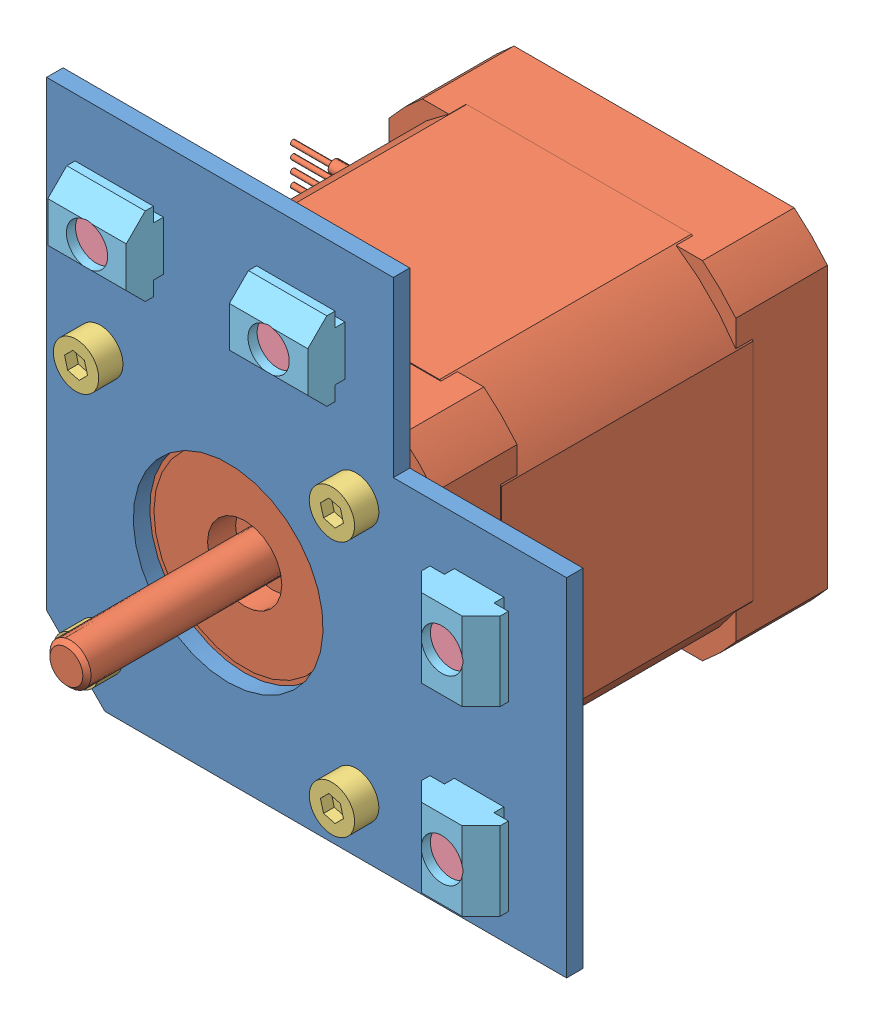
SolidWorks assembly 041XY轴电机1, configuration 默认. Lengths in mm.
Overall size (80 63 71.2).
22 component instances, 6 part files, 25 mates.
Components (placement in the parent):
- XY电机支架-1: XY电机支架 [默认] at (22.6895 35.4643 66.5) x (1 0 0) z (0 -1 0) size (63 2 63)
- 42步进电机-2: 42步进电机 [默认] at (-18.3105 -5.5357 56.5) x (0 1 0) z (1 0 0) size (42.2 71.2 60.1)
- M3_10-1: M3_10 [默认] at (-33.8105 -21.0357 58.5) x (0 1 0) z (1 0 0) size (5.5 12.93 5.5)
- M3_10-2: M3_10 [默认] at (-33.8105 9.9643 58.5) x (0 1 0) z (1 0 0) size (5.5 12.93 5.5)
- M3_10-3: M3_10 [默认] at (-2.8105 -21.0357 58.5) x (0 1 0) z (1 0 0) size (5.5 12.93 5.5)
- M3_10-4: M3_10 [默认] at (-2.8105 9.9643 58.5) x (0 1 0) z (1 0 0) size (5.5 12.93 5.5)
- M5_6-1: M5_6 [默认] at (12.6895 4.4643 72.5) x (1 0 0) z (0 1 0) size (8.5 10.91 8.5)
- M5_6-2: M5_6 [默认] at (12.6895 -17.5357 72.5) x (1 0 0) z (0 1 0) size (8.5 10.91 8.5)
- 欧标20M5滑块螺母-1: 欧标20M5滑块螺母 [默认] at (7.9395 -22.2857 73.6) x (0 1 0) z (-1 0 0) size (9.5 4.5 9.5)
- 欧标20M5滑块螺母-2: 欧标20M5滑块螺母 [默认] at (7.9395 -0.2857 73.6) x (0 1 0) z (-1 0 0) size (9.5 4.5 9.5)
- M5_6-3: M5_6 [默认] at (-30.3105 25.4643 72.5) x (1 0 0) z (0 1 0) size (8.5 10.91 8.5)
- M5_6-4: M5_6 [默认] at (-8.3105 25.4643 72.5) x (1 0 0) z (0 1 0) size (8.5 10.91 8.5)
- 欧标20M5滑块螺母-3: 欧标20M5滑块螺母 [默认] at (-35.0605 30.2143 73.6) x (1 0 0) z (0 1 0) size (9.5 4.5 9.5)
- 欧标20M5滑块螺母-4: 欧标20M5滑块螺母 [默认] at (-13.0605 30.2143 73.6) x (1 0 0) z (0 1 0) size (9.5 4.5 9.5)
- M3_6_1尼龙垫片-1: M3_6_1尼龙垫片 [默认] at (-33.8105 -21.0357 65.5) x (1 0 0) z (0 -1 0) size (6 1 6)
- M3_6_1尼龙垫片-9: M3_6_1尼龙垫片 [默认] at (-33.8105 -21.0357 64.5) x (1 0 0) z (0 -1 0) size (6 1 6)
- M3_6_1尼龙垫片-10: M3_6_1尼龙垫片 [默认] at (-33.8105 9.9643 64.5) x (1 0 0) z (0 -1 0) size (6 1 6)
- M3_6_1尼龙垫片-11: M3_6_1尼龙垫片 [默认] at (-2.8105 -21.0357 64.5) x (1 0 0) z (0 -1 0) size (6 1 6)
- M3_6_1尼龙垫片-12: M3_6_1尼龙垫片 [默认] at (-2.8105 9.9643 64.5) x (1 0 0) z (0 -1 0) size (6 1 6)
- M3_6_1尼龙垫片-6: M3_6_1尼龙垫片 [默认] at (-33.8105 9.9643 65.5) x (1 0 0) z (0 -1 0) size (6 1 6)
- M3_6_1尼龙垫片-7: M3_6_1尼龙垫片 [默认] at (-2.8105 -21.0357 65.5) x (1 0 0) z (0 -1 0) size (6 1 6)
- M3_6_1尼龙垫片-8: M3_6_1尼龙垫片 [默认] at (-2.8105 9.9643 65.5) x (1 0 0) z (0 -1 0) size (6 1 6)
Mates (geometry in assembly coordinates):
- 同心1: concentric: circle of assembly; circle of assembly; circle of XY电机支架-1; circle of 42步进电机-2
- 同心3: concentric: circle of assembly; circle of assembly; circle of XY电机支架-1; circle of 42步进电机-2
- 重合2: coincident: plane of assembly; plane of assembly; plane of XY电机支架-1 through (22.6895 35.4643 68.5) normal (0 0 1); plane of M3_10-1 through (-33.8105 -21.0357 68.5) normal (0 0 -1)
- 同心5: concentric: cylinder of assembly; cylinder of assembly; cylinder of XY电机支架-1 through (-33.8105 -21.0357 66.5) axis (0 0 1) radius 1.75; cylinder of M3_10-1 through (-33.8105 -21.0357 68.5) axis (0 0 -1) radius 1.5
- 重合3: coincident: plane of assembly; plane of assembly; plane of XY电机支架-1 through (22.6895 35.4643 66.5) normal (0 0 -1); plane of M5_6-1 through (12.6895 4.4643 66.5) normal (0 0 1)
- 重合4: coincident: plane of assembly; plane of assembly; plane of XY电机支架-1 through (22.6895 35.4643 66.5) normal (0 0 -1); plane of M5_6-2 through (12.6895 -17.5357 66.5) normal (0 0 1)
- 同心6: concentric: cylinder of assembly; cylinder of assembly; cylinder of XY电机支架-1 through (12.6895 4.4643 66.5) axis (0 0 1) radius 2.75; cylinder of M5_6-1 through (12.6895 4.4643 66.5) axis (0 0 1) radius 2.5
- 同心7: concentric: cylinder of assembly; cylinder of assembly; cylinder of XY电机支架-1 through (12.6895 -17.5357 66.5) axis (0 0 1) radius 2.75; cylinder of M5_6-2 through (12.6895 -17.5357 66.5) axis (0 0 1) radius 2.5
- 距离2: distance = 1.8 mm: plane of assembly; plane of assembly; plane of XY电机支架-1 through (22.6895 35.4643 68.5) normal (0 0 1); plane of 欧标20M5滑块螺母-2 through (7.9395 -0.2857 70.3) normal (0 0 -1)
- 距离3: distance = 1.8 mm: plane of assembly; plane of assembly; plane of XY电机支架-1 through (22.6895 35.4643 68.5) normal (0 0 1); plane of 欧标20M5滑块螺母-1 through (7.9395 -22.2857 70.3) normal (0 0 -1)
- 同心8: concentric: cylinder of assembly; cylinder of assembly; cylinder of M5_6-2 through (12.6895 -17.5357 66.5) axis (0 0 1) radius 2.5; cylinder of 欧标20M5滑块螺母-1 through (12.6895 -17.5357 73.6) axis (0 0 -1) radius 2.5
- 同心10: concentric: cylinder of assembly; cylinder of assembly; cylinder of M5_6-1 through (12.6895 4.4643 66.5) axis (0 0 1) radius 2.5; cylinder of 欧标20M5滑块螺母-2 through (12.6895 4.4643 73.6) axis (0 0 -1) radius 2.5
- 重合5: coincident: plane of assembly; plane of assembly; plane of XY电机支架-1 through (22.6895 35.4643 66.5) normal (0 0 -1); plane of M5_6-4 through (-8.3105 25.4643 66.5) normal (0 0 1)
- 重合6: coincident: plane of assembly; plane of assembly; plane of XY电机支架-1 through (22.6895 35.4643 66.5) normal (0 0 -1); plane of M5_6-3 through (-30.3105 25.4643 66.5) normal (0 0 1)
- 同心11: concentric: cylinder of assembly; cylinder of assembly; cylinder of XY电机支架-1 through (-8.3105 25.4643 66.5) axis (0 0 1) radius 2.75; cylinder of M5_6-4 through (-8.3105 25.4643 66.5) axis (0 0 1) radius 2.5
- 同心12: concentric: cylinder of assembly; cylinder of assembly; cylinder of XY电机支架-1 through (-30.3105 25.4643 66.5) axis (0 0 1) radius 2.75; cylinder of M5_6-3 through (-30.3105 25.4643 66.5) axis (0 0 1) radius 2.5
- 距离4: distance = 1.8 mm: plane of assembly; plane of assembly; plane of XY电机支架-1 through (22.6895 35.4643 68.5) normal (0 0 1); plane of 欧标20M5滑块螺母-4 through (-13.0605 30.2143 70.3) normal (0 0 -1)
- 距离5: distance = 1.8 mm: plane of assembly; plane of assembly; plane of XY电机支架-1 through (22.6895 35.4643 68.5) normal (0 0 1); plane of 欧标20M5滑块螺母-3 through (-35.0605 30.2143 70.3) normal (0 0 -1)
- 同心13: concentric: cylinder of assembly; cylinder of assembly; cylinder of M5_6-4 through (-8.3105 25.4643 66.5) axis (0 0 1) radius 2.5; cylinder of 欧标20M5滑块螺母-4 through (-8.3105 25.4643 73.6) axis (0 0 -1) radius 2.5
- 同心14: concentric: cylinder of assembly; cylinder of assembly; cylinder of M5_6-3 through (-30.3105 25.4643 66.5) axis (0 0 1) radius 2.5; cylinder of 欧标20M5滑块螺母-3 through (-30.3105 25.4643 73.6) axis (0 0 -1) radius 2.5
- 重合7: coincident: plane of assembly; plane of assembly; plane of M3_6_1尼龙垫片-1 through (-33.8105 -21.0357 65.5) normal (0 0 -1); plane of M3_6_1尼龙垫片-9 through (-33.8105 -21.0357 65.5) normal (0 0 1)
- 同心15: concentric: cylinder of assembly; cylinder of assembly; cylinder of M3_6_1尼龙垫片-1 through (-33.8105 -21.0357 66.5) axis (0 0 -1) radius 1.5; cylinder of M3_6_1尼龙垫片-9 through (-33.8105 -21.0357 65.5) axis (0 0 -1) radius 1.5
- 重合8: coincident: plane of assembly; plane of assembly; plane of XY电机支架-1 through (22.6895 35.4643 66.5) normal (0 0 -1); plane of M3_6_1尼龙垫片-1 through (-33.8105 -21.0357 66.5) normal (0 0 1)
- 重合9: coincident: plane of assembly; plane of assembly; plane of 42步进电机-2 through (-18.3105 -5.5357 64.5) normal (0 0 1); plane of M3_6_1尼龙垫片-9 through (-33.8105 -21.0357 64.5) normal (0 0 -1)
- 同心16: concentric: cylinder of assembly; cylinder of assembly; cylinder of M3_10-1 through (-33.8105 -21.0357 68.5) axis (0 0 -1) radius 1.5; cylinder of M3_6_1尼龙垫片-1 through (-33.8105 -21.0357 66.5) axis (0 0 -1) radius 1.5
